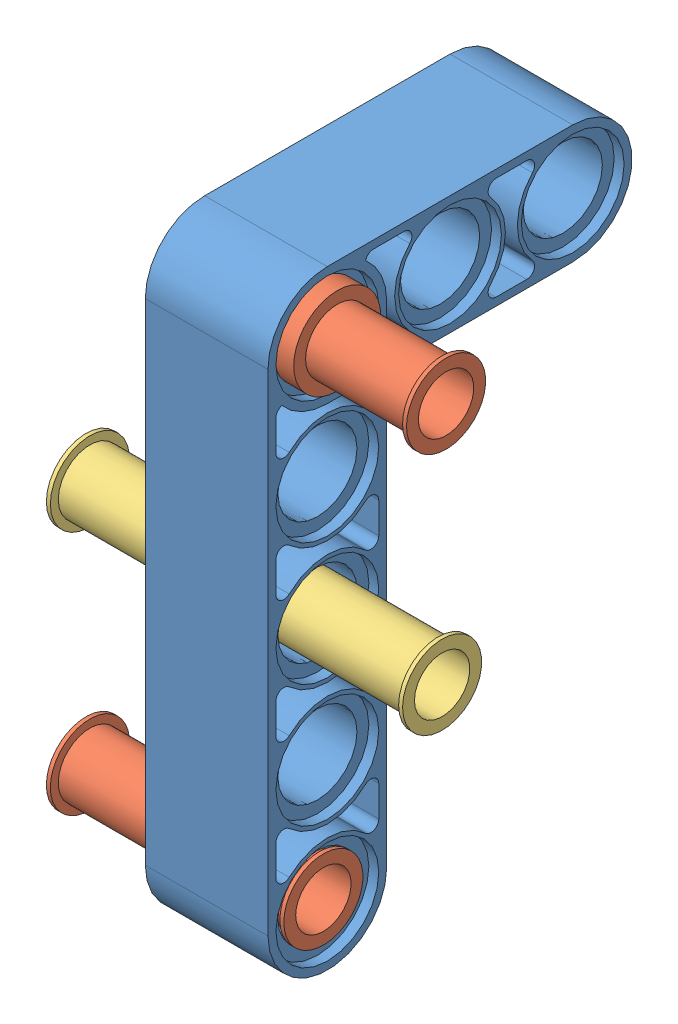
SolidWorks assembly left_connector, configuration Default. Lengths in mm.
Overall size (23.11 39.12 23.37).
4 component instances, 3 part files, 12 mates.
Components (placement in the parent):
- L_Three_Five_90degrees-1: L_Three_Five_90degrees [Default] x (0 1 0) z (-1 0 0) size (39.12 23.37 7.87)
- BlackConnectorSmall-1: BlackConnectorSmall [Default] at (-7.366 7.874 0) size (15.24 5.59 5.59)
- BlackConnectorSmall-2: BlackConnectorSmall [Default] at (-15.24 -23.622 0) size (15.24 5.59 5.59)
- BlueConnectorLong-1: BlueConnectorLong [Default] at (-15.24 -7.874 0) size (22.86 5.59 5.59)
Mates (geometry in assembly coordinates):
- Coincident1: coincident aligned: plane of L_Three_Five_90degrees-1; plane of assembly through (0 0 0) normal (0 1 0)
- Coincident2: coincident anti-aligned: plane of L_Three_Five_90degrees-1; plane of assembly through (0 0 0) normal (0 0 1)
- Coincident3: coincident anti-aligned: plane of L_Three_Five_90degrees-1 through (0 0 0) normal (-1 0 0); plane of assembly through (0 0 0) normal (1 0 0)
- Concentric1: concentric anti-aligned: cylinder of L_Three_Five_90degrees-1 through (-3.81 7.874 0) axis (1 0 0) radius 2.54; cylinder of BlackConnectorSmall-1 through (0.1276 7.874 0) axis (-1 0 0) radius 2.032
- Parallel1: parallel aligned: plane of BlackConnectorSmall-1 through (0.1276 7.874 0) normal (0 1 0); plane of assembly through (0 0 0) normal (0 1 0)
- Concentric2: concentric anti-aligned: cylinder of L_Three_Five_90degrees-1 through (-3.81 -23.622 0) axis (1 0 0) radius 2.54; cylinder of BlackConnectorSmall-2 through (-15.24 -23.622 0) axis (-1 0 0) radius 2.032
- Parallel2: parallel aligned: plane of BlackConnectorSmall-2 through (-15.24 -23.622 0) normal (0 1 0); plane of assembly through (0 0 0) normal (0 1 0)
- Concentric3: concentric anti-aligned: cylinder of L_Three_Five_90degrees-1 through (-3.81 -7.874 0) axis (1 0 0) radius 2.54; cylinder of BlueConnectorLong-1 through (-15.24 -7.874 0) axis (-1 0 0) radius 2.032
- Coincident8: coincident anti-aligned: plane of L_Three_Five_90degrees-1 through (-6.985 -7.874 0) normal (-1 0 0); plane of BlueConnectorLong-1 through (-6.985 -5.842 0) normal (1 0 0)
- Parallel3: parallel aligned: plane of BlueConnectorLong-1 through (-15.24 -7.874 0) normal (0 1 0); plane of assembly
- Coincident9: coincident anti-aligned: plane of L_Three_Five_90degrees-1 through (-6.985 -23.622 0) normal (-1 0 0); plane of BlackConnectorSmall-2 through (-6.985 -21.59 0) normal (1 0 0)
- Coincident10: coincident anti-aligned: plane of L_Three_Five_90degrees-1 through (-0.381 7.874 0) normal (1 0 0); plane of BlackConnectorSmall-1 through (-0.381 10.668 0) normal (-1 0 0)
